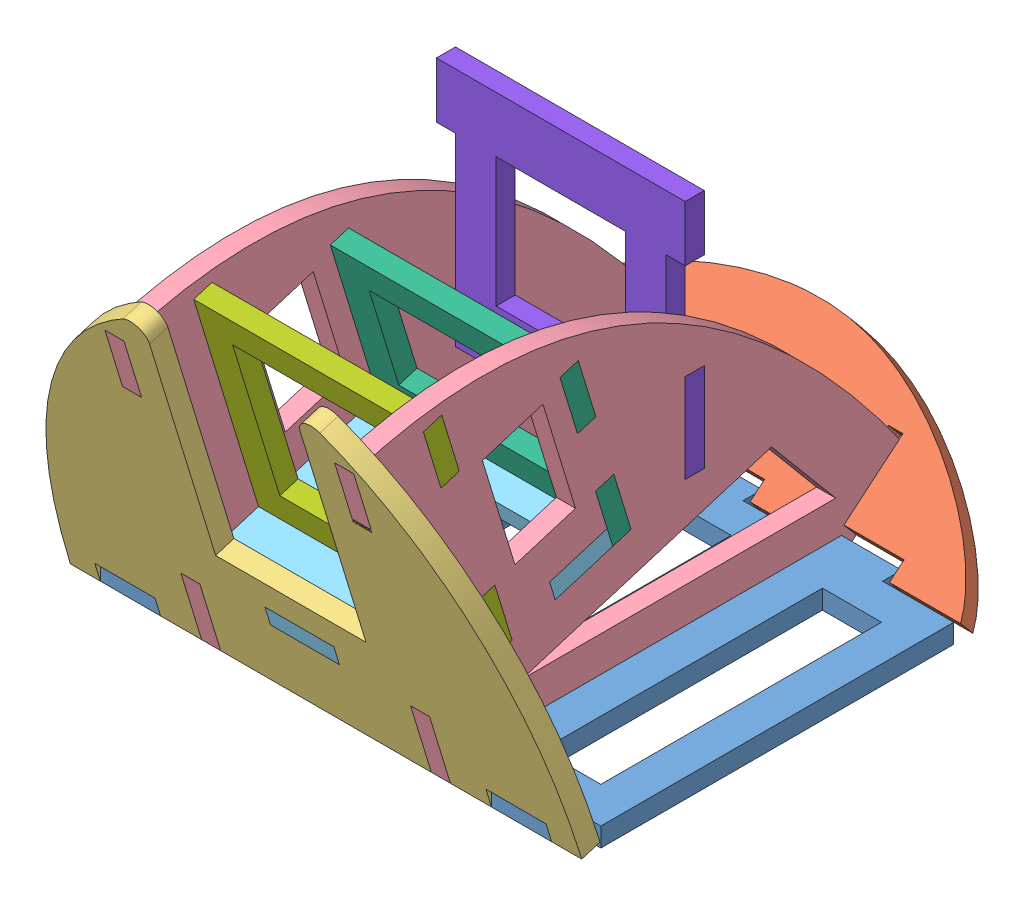
SolidWorks assembly Pod, configuration Default. Lengths in mm.
Overall size (85 64.23 102.11).
9 component instances, 8 part files, 18 mates.
Components (placement in the parent):
- Base-1: Base [Default] at (-1.2782 40.8171 94.062) size (85 3.17 65)
- FrontBase-1: FrontBase [Default] at (-1.2782 40.8171 29.062) x (1 0 0) z (0 -0.642788 0.766044) size (85 3.17 25.52)
- RearBase-1: RearBase [Default] at (-1.2782 41.7454 91.0257) x (1 0 0) z (0 -0.956305 -0.292372) size (85 3.17 60.05)
- Vertical Support-2: Vertical Support [Default] at (58.7218 40.8171 94.062) x (0 0 -1) z (1 0 0) size (92.57 60.51 3.17)
- Vertical Support-3: Vertical Support [Default] at (20.5468 40.8171 94.062) x (0 0 -1) z (1 0 0) size (92.57 60.51 3.17)
- Holder Bottom-1: Holder Bottom [Default] at (20.5468 52.1254 97.5193) x (1 0 0) z (0 -0.292372 0.956305) size (41.35 3.17 35)
- Front Holder-1: Front Holder [Default] at (20.5468 62.3584 64.0486) x (1 0 0) z (0 -0.956305 -0.292372) size (41.35 3.17 30)
- Rear Holder-1: Rear Holder [Default] at (20.5468 93.6375 98.5514) x (1 0 0) z (0 0.956305 0.292372) size (41.35 3.17 40)
- Camera Mount-1: Camera Mount [Default] at (20.5468 105.0441 55.0478) x (1 0 0) z (0 1 0) size (41.35 3.17 40)
Mates (geometry in assembly coordinates):
- Angle1: planar angle = 1.867502 rad anti-aligned: plane of RearBase-1 through (-1.2782 40.8171 94.062) normal (0 -0.292372 0.956305); plane of Base-1 through (-1.2782 40.8171 94.062) normal (0 -1 0)
- Angle2: planar angle = 2.443461 rad anti-aligned: plane of Base-1 through (-1.2782 40.8171 94.062) normal (0 -1 0); plane of FrontBase-1 through (-1.2782 40.8171 29.062) normal (0 -0.766044 -0.642788)
- Coincident9: coincident aligned: plane of Base-1 through (-1.2782 40.8171 94.062) normal (0 -1 0); plane of Vertical Support-2 through (61.8968 40.8171 94.062) normal (0 -1 0)
- Coincident13: coincident anti-aligned: line of RearBase-1 through (-1.2782 40.8171 94.062) axis (1 0 0); line of Vertical Support-2 through (61.8968 40.8171 94.062) axis (-1 0 0)
- Distance2: distance = 25 mm anti-aligned: plane of Base-1 through (83.7218 43.9921 94.062) normal (1 0 0); plane of Vertical Support-2 through (58.7218 90.5856 61.1257) normal (-1 0 0)
- Coincident16: coincident aligned: plane of Base-1 through (-1.2782 40.8171 94.062) normal (0 -1 0); plane of Vertical Support-3 through (23.7218 40.8171 94.062) normal (0 -1 0)
- Coincident17: coincident anti-aligned: line of RearBase-1 through (-1.2782 40.8171 94.062) axis (1 0 0); line of Vertical Support-3 through (23.7218 40.8171 94.062) axis (-1 0 0)
- Distance3: distance = 35 mm anti-aligned: plane of Vertical Support-2 through (58.7218 90.5856 61.1257) normal (-1 0 0); plane of Vertical Support-3 through (23.7218 90.5856 61.1257) normal (1 0 0)
- Coincident19: coincident aligned: plane of RearBase-1 through (-1.2782 40.8171 94.062) normal (0 -0.292372 0.956305); plane of Holder Bottom-1 through (20.5468 55.1616 98.4476) normal (0 -0.292372 0.956305)
- Coincident20: coincident aligned: plane of Vertical Support-3 through (20.5468 90.5856 61.1257) normal (-1 0 0); plane of Holder Bottom-1 through (20.5468 55.1616 98.4476) normal (-1 0 0)
- Coincident22: coincident aligned: plane of Holder Bottom-1 through (20.5468 65.3947 64.9769) normal (0 0.292372 -0.956305); plane of Front Holder-1 through (20.5468 62.3584 64.0486) normal (0 0.292372 -0.956305)
- Coincident23: coincident aligned: plane of Vertical Support-3 through (20.5468 90.5856 61.1257) normal (-1 0 0); plane of Front Holder-1 through (20.5468 61.4301 67.0849) normal (-1 0 0)
- Coincident24: coincident aligned: plane of Holder Bottom-1 through (20.5468 52.1254 97.5193) normal (0 -0.956305 -0.292372); plane of Front Holder-1 through (20.5468 61.4301 67.0849) normal (0 -0.956305 -0.292372)
- Coincident25: coincident aligned: plane of Holder Bottom-1 through (20.5468 52.1254 97.5193) normal (0 -0.956305 -0.292372); plane of Rear Holder-1 through (20.5468 56.3136 83.8202) normal (0 -0.956305 -0.292372)
- Coincident26: coincident aligned: plane of Vertical Support-2 through (61.8968 90.5856 61.1257) normal (1 0 0); plane of Rear Holder-1 through (61.8968 94.5658 95.5151) normal (1 0 0)
- Distance4: distance = 17.5 mm anti-aligned: plane of Front Holder-1 through (20.5468 61.4301 67.0849) normal (0 -0.292372 0.956305); plane of Rear Holder-1 through (20.5468 94.5658 95.5151) normal (0 0.292372 -0.956305)
- Coincident28: coincident aligned: plane of Vertical Support-3 through (20.5468 90.5856 61.1257) normal (-1 0 0); plane of Camera Mount-1 through (20.5468 105.0441 51.8728) normal (-1 0 0)
- Parallel4: parallel anti-aligned: plane of Base-1 through (-1.2782 40.8171 94.062) normal (0 -1 0); plane of Camera Mount-1 through (20.5468 105.0441 51.8728) normal (0 1 0)
